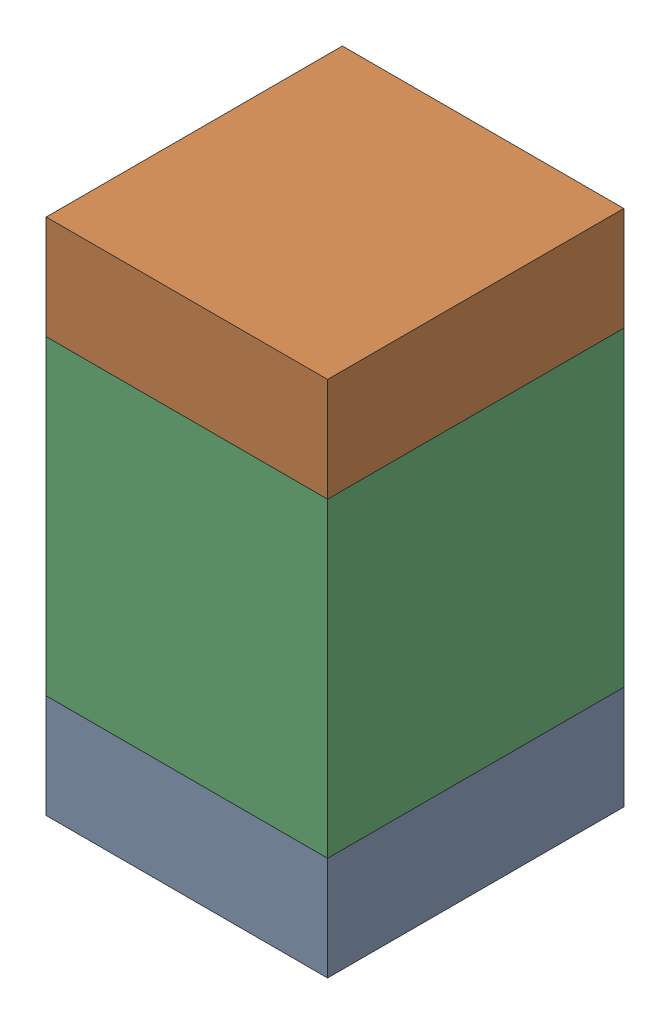
SolidWorks assembly C2, configuration Default. Lengths in mm.
Overall size (0.95 1.75 1).
6 component instances, 2 part files, 0 mates.
Components (placement in the parent):
- 959208664-1: 959208664 [Default] at (140.8925 85.698 0) size (0.95 0.35 1)
  - Extruded-14-1: Extruded-14 [Default] at origin size (0.95 0.35 1)
- 959208664-2: 959208664 [Default] at (140.8925 87.098 0) size (0.95 0.35 1)
  - Extruded-14-1: Extruded-14 [Default] at origin size (0.95 0.35 1)
- 959208528-1: 959208528 [Default] at (140.8925 86.398 0) size (0.95 1.05 1)
  - Extruded-15-1: Extruded-15 [Default] at origin size (0.95 1.05 1)
